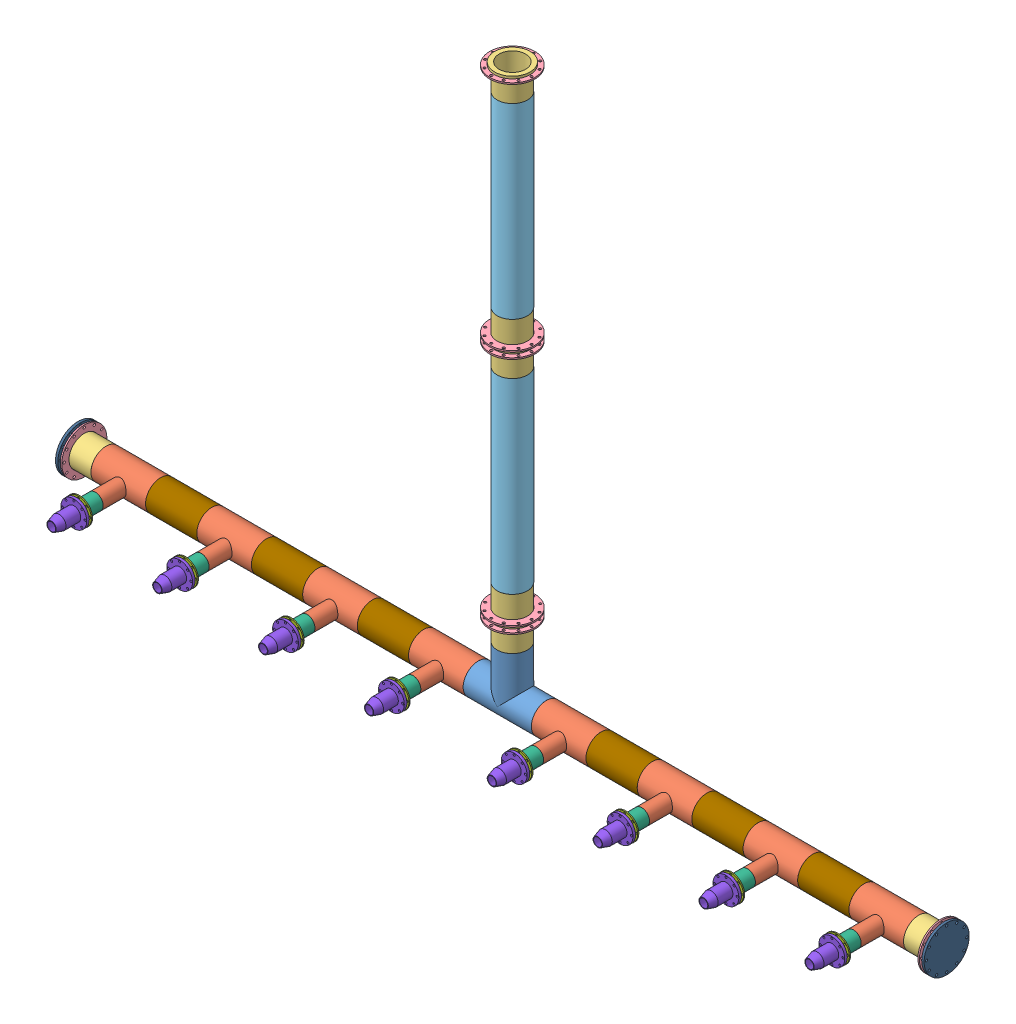
SolidWorks assembly Unflanged_Manifold_Assembly, configuration Default. Lengths in mm.
Overall size (9295.13 6167.88 1145.53).
57 component instances, 10 part files, 27 mates.
Components (placement in the parent):
- 12_NOM_Tee_Branch-1: 12_NOM_Tee_Branch [Default] x (0 1 0) z (-1 0 0) size (688.98 323.85 730.25)
- 12_to_6_Tee_Reducer-1: 12_to_6_Tee_Reducer [Default] at (657.225 0 0) x (1 0 0) z (0 -1 0) size (584.2 568.32 323.85)
- 12_NOM_Flange_Adapter-18: 12_NOM_Flange_Adapter [Default] at (0 801.37 0) x (0 -1 0) z (-0.329738 0 0.944073) size (274.32 381 381)
- Class_150_Slip-On_Plate_Flange-18: Class_150_Slip-On_Plate_Flange [Default] at (0 760.095 0) x (0.998909 0 0.04671) z (0 1 0) size (482.6 482.6 15.88)
- 12_NOM_Flange_Adapter-19: 12_NOM_Flange_Adapter [Default] at (0 801.37 0) x (0 1 0) z (0.329738 0 -0.944073) size (274.32 381 381)
- Class_150_Slip-On_Plate_Flange-19: Class_150_Slip-On_Plate_Flange [Default] at (0 842.645 0) x (0.998909 0 0.04671) z (0 -1 0) size (482.6 482.6 15.88)
- 12_NOM_Pipe_Segment-1: 12_NOM_Pipe_Segment [Default] at (0 3075.69 0) x (0 -1 0) z (0.028781 0 0.999586) size (2000 323.85 323.85)
- 12_NOM_Flange_Adapter-20: 12_NOM_Flange_Adapter [Default] at (0 3350.01 0) x (0 -1 0) z (-0.329738 0 0.944073) size (274.32 381 381)
- Class_150_Slip-On_Plate_Flange-20: Class_150_Slip-On_Plate_Flange [Default] at (0 3308.735 0) x (-0.998909 0 -0.04671) z (0 1 0) size (482.6 482.6 15.88)
- 12_NOM_Flange_Adapter-21: 12_NOM_Flange_Adapter [Default] at (0 5898.65 0) x (0 -1 0) z (-0.329738 0 0.944073) size (274.32 381 381)
- Class_150_Slip-On_Plate_Flange-21: Class_150_Slip-On_Plate_Flange [Default] at (0 5857.375 0) x (-0.998909 0 -0.04671) z (0 1 0) size (482.6 482.6 15.88)
- 12_NOM_Flange_Adapter-22: 12_NOM_Flange_Adapter [Default] at (0 3350.01 0) x (0 1 0) z (0.329738 0 -0.944073) size (274.32 381 381)
- Class_150_Slip-On_Plate_Flange-22: Class_150_Slip-On_Plate_Flange [Default] at (0 3375.41 0) x (0.998909 0 0.04671) z (0 1 0) size (482.6 482.6 15.88)
- 12_NOM_Pipe_Segment-2: 12_NOM_Pipe_Segment [Default] at (0 3624.33 0) x (0 1 0) z (-0.028781 0 -0.999586) size (2000 323.85 323.85)
- 6_NOM_Flange_Adapter-2: 6_NOM_Flange_Adapter [Default] at (657.225 0 609.6) x (0 0 -1) z (0.910925 0.412572 0) size (203.2 215.9 215.9)
- 6_NOM_Class_150_Slip-On_Plate_Flange-1: 6_NOM_Class_150_Slip-On_Plate_Flange [Default] at (657.225 0 576.58) size (279.4 279.4 12.7)
- Nozzle(Flanged)-1: Nozzle(Flanged) [Default] at (657.225 0 876.3) x (0 0 -1) z (0.92388 0.382683 0) size (266.7 275.84 275.84)
- 12_NOM_Horizontal_Pipe_Segment-1: 12_NOM_Horizontal_Pipe_Segment [Default] at (949.325 0 0) x (1 0 0) z (0 0.450094 0.892981) size (548.64 323.85 323.85)
- 12_to_6_Tee_Reducer-19: 12_to_6_Tee_Reducer [Default] at (1790.065 0 0) x (-1 0 0) z (0 1 0) size (584.2 568.32 323.85)
- 6_NOM_Flange_Adapter-10: 6_NOM_Flange_Adapter [Default] at (1790.065 0 609.6) x (0 0 -1) z (0.910925 -0.412572 0) size (203.2 215.9 215.9)
- 6_NOM_Class_150_Slip-On_Plate_Flange-9: 6_NOM_Class_150_Slip-On_Plate_Flange [Default] at (1790.065 0 576.58) size (279.4 279.4 12.7)
- Nozzle(Flanged)-9: Nozzle(Flanged) [Default] at (1790.065 0 876.3) x (0 0 -1) z (-0.92388 0.382683 0) size (266.7 275.84 275.84)
- 12_NOM_Horizontal_Pipe_Segment-2: 12_NOM_Horizontal_Pipe_Segment [Default] at (2630.805 0 0) x (-1 0 0) z (0 -0.450094 -0.892981) size (548.64 323.85 323.85)
- 12_to_6_Tee_Reducer-20: 12_to_6_Tee_Reducer [Default] at (2922.905 0 0) x (-1 0 0) z (0 1 0) size (584.2 568.32 323.85)
- 6_NOM_Flange_Adapter-11: 6_NOM_Flange_Adapter [Default] at (2922.905 0 609.6) x (0 0 -1) z (0.910925 -0.412572 0) size (203.2 215.9 215.9)
- Nozzle(Flanged)-10: Nozzle(Flanged) [Default] at (2922.905 0 876.3) x (0 0 -1) z (-0.92388 0.382683 0) size (266.7 275.84 275.84)
- 6_NOM_Class_150_Slip-On_Plate_Flange-10: 6_NOM_Class_150_Slip-On_Plate_Flange [Default] at (2922.905 0 576.58) size (279.4 279.4 12.7)
- 12_NOM_Horizontal_Pipe_Segment-3: 12_NOM_Horizontal_Pipe_Segment [Default] at (3215.005 0 0) x (1 0 0) z (0 0.450094 0.892981) size (548.64 323.85 323.85)
- 12_to_6_Tee_Reducer-21: 12_to_6_Tee_Reducer [Default] at (4055.745 0 0) x (1 0 0) z (0 -1 0) size (584.2 568.32 323.85)
- 6_NOM_Flange_Adapter-12: 6_NOM_Flange_Adapter [Default] at (4055.745 0 609.6) x (0 0 -1) z (0.910925 0.412572 0) size (203.2 215.9 215.9)
- 6_NOM_Class_150_Slip-On_Plate_Flange-11: 6_NOM_Class_150_Slip-On_Plate_Flange [Default] at (4055.745 0 576.58) size (279.4 279.4 12.7)
- Nozzle(Flanged)-11: Nozzle(Flanged) [Default] at (4055.745 0 876.3) x (0 0 -1) z (-0.92388 -0.382683 0) size (266.7 275.84 275.84)
- 12_NOM_Flange_Adapter-23: 12_NOM_Flange_Adapter [Default] at (4622.165 0 0) x (-1 0 0) z (0 -0.680898 -0.732378) size (274.32 381 381)
- Class_150_Slip-On_Plate_Flange-23: Class_150_Slip-On_Plate_Flange [Default] at (4580.89 0 0) x (0 0 -1) z (1 0 0) size (482.6 482.6 15.88)
- 12_NOM_Blind_Flange-3: 12_NOM_Blind_Flange [Default] at (4647.565 0 0) x (0 0 1) z (-1 0 0) size (482.6 482.6 25.4)
- 12_NOM_Flange_Adapter-24: 12_NOM_Flange_Adapter [Default] at (-4622.165 0 0) x (1 0 0) z (0 0.680898 0.732378) size (274.32 381 381)
- 12_NOM_Horizontal_Pipe_Segment-4: 12_NOM_Horizontal_Pipe_Segment [Default] at (-949.325 0 0) x (-1 0 0) z (0 -0.450094 -0.892981) size (548.64 323.85 323.85)
- 12_NOM_Horizontal_Pipe_Segment-5: 12_NOM_Horizontal_Pipe_Segment [Default] at (-3215.005 0 0) x (-1 0 0) z (0 -0.450094 -0.892981) size (548.64 323.85 323.85)
- Nozzle(Flanged)-12: Nozzle(Flanged) [Default] at (-4055.745 0 876.3) x (0 0 -1) z (-0.92388 0.382683 0) size (266.7 275.84 275.84)
- 12_to_6_Tee_Reducer-22: 12_to_6_Tee_Reducer [Default] at (-2922.905 0 0) x (1 0 0) z (0 -1 0) size (584.2 568.32 323.85)
- 6_NOM_Class_150_Slip-On_Plate_Flange-12: 6_NOM_Class_150_Slip-On_Plate_Flange [Default] at (-4055.745 0 576.58) x (-1 0 0) z (0 0 1) size (279.4 279.4 12.7)
- 6_NOM_Class_150_Slip-On_Plate_Flange-13: 6_NOM_Class_150_Slip-On_Plate_Flange [Default] at (-2922.905 0 576.58) x (-1 0 0) z (0 0 1) size (279.4 279.4 12.7)
- Nozzle(Flanged)-13: Nozzle(Flanged) [Default] at (-2922.905 0 876.3) x (0 0 -1) z (-0.92388 -0.382683 0) size (266.7 275.84 275.84)
- 6_NOM_Flange_Adapter-13: 6_NOM_Flange_Adapter [Default] at (-2922.905 0 609.6) x (0 0 -1) z (0.910925 0.412572 0) size (203.2 215.9 215.9)
- 12_NOM_Horizontal_Pipe_Segment-6: 12_NOM_Horizontal_Pipe_Segment [Default] at (-2630.805 0 0) x (1 0 0) z (0 0.450094 0.892981) size (548.64 323.85 323.85)
- 6_NOM_Flange_Adapter-14: 6_NOM_Flange_Adapter [Default] at (-4055.745 0 609.6) x (0 0 -1) z (0.910925 -0.412572 0) size (203.2 215.9 215.9)
- 12_to_6_Tee_Reducer-23: 12_to_6_Tee_Reducer [Default] at (-4055.745 0 0) x (-1 0 0) z (0 1 0) size (584.2 568.32 323.85)
- 12_to_6_Tee_Reducer-24: 12_to_6_Tee_Reducer [Default] at (-1790.065 0 0) x (1 0 0) z (0 -1 0) size (584.2 568.32 323.85)
- Class_150_Slip-On_Plate_Flange-24: Class_150_Slip-On_Plate_Flange [Default] at (-4580.89 0 0) x (0 0 -1) z (-1 0 0) size (482.6 482.6 15.88)
- 12_NOM_Blind_Flange-4: 12_NOM_Blind_Flange [Default] at (-4622.165 0 0) x (0 0 1) z (-1 0 0) size (482.6 482.6 25.4)
- 12_to_6_Tee_Reducer-25: 12_to_6_Tee_Reducer [Default] at (-657.225 0 0) x (-1 0 0) z (0 1 0) size (584.2 568.32 323.85)
- Nozzle(Flanged)-14: Nozzle(Flanged) [Default] at (-657.225 0 876.3) x (0 0 -1) z (0.92388 -0.382683 0) size (266.7 275.84 275.84)
- 6_NOM_Class_150_Slip-On_Plate_Flange-14: 6_NOM_Class_150_Slip-On_Plate_Flange [Default] at (-657.225 0 576.58) x (-1 0 0) z (0 0 1) size (279.4 279.4 12.7)
- 6_NOM_Flange_Adapter-15: 6_NOM_Flange_Adapter [Default] at (-657.225 0 609.6) x (0 0 -1) z (0.910925 -0.412572 0) size (203.2 215.9 215.9)
- 6_NOM_Flange_Adapter-16: 6_NOM_Flange_Adapter [Default] at (-1790.065 0 609.6) x (0 0 -1) z (0.910925 0.412572 0) size (203.2 215.9 215.9)
- 6_NOM_Class_150_Slip-On_Plate_Flange-15: 6_NOM_Class_150_Slip-On_Plate_Flange [Default] at (-1790.065 0 576.58) x (-1 0 0) z (0 0 1) size (279.4 279.4 12.7)
- Nozzle(Flanged)-15: Nozzle(Flanged) [Default] at (-1790.065 0 876.3) x (0 0 -1) z (-0.92388 -0.382683 0) size (266.7 275.84 275.84)
Mates (geometry in assembly coordinates):
- Concentric1: concentric aligned: cylinder of 12_NOM_Tee_Branch-1 through (-365.125 0 0) axis (1 0 0) radius 141.732
- Concentric2: concentric aligned: cylinder of 12_NOM_Tee_Branch-1 through (0 -400.8786 0) axis (0 1 0) radius 141.732
- Concentric3: concentric anti-aligned: cylinder of 12_NOM_Tee_Branch-1 through (-365.125 0 0) axis (1 0 0) radius 141.732; cylinder of 12_to_6_Tee_Reducer-1 through (657.225 0 0) axis (-1 0 0) radius 141.732
- Parallel1: parallel aligned: plane of 12_to_6_Tee_Reducer-1 through (657.225 0 406.4) normal (0 0 1)
- Coincident3: coincident anti-aligned: plane of 12_NOM_Tee_Branch-1 through (365.125 0 0) normal (1 0 0); plane of 12_to_6_Tee_Reducer-1 through (365.125 0 161.925) normal (-1 0 0)
- Concentric11: concentric aligned: cylinder of 12_NOM_Tee_Branch-1 through (0 -400.8786 0) axis (0 1 0) radius 141.732; cylinder of 12_NOM_Flange_Adapter-18 through (0 801.37 0) axis (0 1 0) radius 141.732
- Coincident11: coincident anti-aligned: plane of 12_NOM_Tee_Branch-1 through (0 527.05 0) normal (0 1 0); plane of 12_NOM_Flange_Adapter-18 through (133.8053 527.05 46.7344) normal (0 -1 0)
- Concentric12: concentric anti-aligned: cylinder of 12_NOM_Flange_Adapter-18 through (0 801.37 0) axis (0 1 0) radius 161.925; cylinder of Class_150_Slip-On_Plate_Flange-18 through (0 775.97 0) axis (0 -1 0) radius 163.576
- Coincident13: coincident anti-aligned: plane of 12_NOM_Flange_Adapter-18 through (152.869 775.97 53.3928) normal (0 -1 0); plane of Class_150_Slip-On_Plate_Flange-18 through (0 775.97 0) normal (0 1 0)
- Concentric13: concentric anti-aligned: cylinder of 12_NOM_Flange_Adapter-19 through (0 801.37 0) axis (0 -1 0) radius 141.732; cylinder of 12_NOM_Pipe_Segment-1 through (0 3075.69 0) axis (0 1 0) radius 141.732
- Coincident14: coincident anti-aligned: plane of 12_NOM_Flange_Adapter-19 through (133.8053 1075.69 46.7344) normal (0 1 0); plane of 12_NOM_Pipe_Segment-1 through (141.6733 1075.69 -4.0792) normal (0 -1 0)
- Concentric16: concentric aligned: cylinder of 12_to_6_Tee_Reducer-1 through (657.225 0 -208.306) axis (0 0 1) radius 73.6473; cylinder of 6_NOM_Flange_Adapter-2 through (657.225 0 609.6) axis (0 0 1) radius 73.6473
- Coincident16: coincident anti-aligned: plane of 12_to_6_Tee_Reducer-1 through (657.225 0 406.4) normal (0 0 1); plane of 6_NOM_Flange_Adapter-2 through (626.8402 67.0872 406.4) normal (0 0 -1)
- Concentric17: concentric anti-aligned: cylinder of 6_NOM_Flange_Adapter-2 through (657.225 0 609.6) axis (0 0 1) radius 84.1375; cylinder of 6_NOM_Class_150_Slip-On_Plate_Flange-1 through (657.225 0 589.28) axis (0 0 -1) radius 84.1375
- Coincident17: coincident anti-aligned: plane of 6_NOM_Flange_Adapter-2 through (622.5122 76.643 589.28) normal (0 0 -1); plane of 6_NOM_Class_150_Slip-On_Plate_Flange-1 through (657.225 0 589.28) normal (0 0 1)
- Concentric18: concentric aligned: cylinder of 6_NOM_Flange_Adapter-2 through (657.225 0 609.6) axis (0 0 1) radius 73.6473; cylinder of Nozzle(Flanged)-1 through (657.225 0 876.3) axis (0 0 1) radius 68.795
- Coincident18: coincident anti-aligned: plane of 6_NOM_Flange_Adapter-2 through (612.6879 98.3344 609.6) normal (0 0 1); plane of Nozzle(Flanged)-1 through (657.225 0 609.6) normal (0 0 -1)
- Concentric19: concentric aligned: cylinder of 6_NOM_Class_150_Slip-On_Plate_Flange-1 through (657.225 120.65 589.28) axis (0 0 -1) radius 11.176; cylinder of Nozzle(Flanged)-1 through (657.225 120.65 609.6) axis (0 0 -1) radius 11.176
- Concentric21: concentric aligned: cylinder of 12_to_6_Tee_Reducer-1 through (657.225 0 0) axis (-1 0 0) radius 141.732; cylinder of 12_NOM_Horizontal_Pipe_Segment-1 through (949.325 0 0) axis (-1 0 0) radius 141.732
- Coincident22: coincident anti-aligned: plane of 12_to_6_Tee_Reducer-1 through (949.325 0 161.925) normal (1 0 0); plane of 12_NOM_Horizontal_Pipe_Segment-1 through (949.325 126.564 -63.7927) normal (-1 0 0)
- Concentric22: concentric anti-aligned: cylinder of 12_to_6_Tee_Reducer-21 through (4055.745 0 0) axis (-1 0 0) radius 141.732; cylinder of 12_NOM_Flange_Adapter-23 through (4622.165 0 0) axis (1 0 0) radius 141.732
- Coincident23: coincident anti-aligned: plane of 12_to_6_Tee_Reducer-21 through (4347.845 0 161.925) normal (1 0 0); plane of 12_NOM_Flange_Adapter-23 through (4347.845 103.8015 -96.505) normal (-1 0 0)
- Concentric23: concentric anti-aligned: cylinder of 12_NOM_Flange_Adapter-23 through (4622.165 0 0) axis (1 0 0) radius 161.925; cylinder of Class_150_Slip-On_Plate_Flange-23 through (4596.765 0 0) axis (-1 0 0) radius 163.576
- Coincident24: coincident anti-aligned: plane of 12_NOM_Flange_Adapter-23 through (4596.765 118.5904 -110.2544) normal (-1 0 0); plane of Class_150_Slip-On_Plate_Flange-23 through (4596.765 0 0) normal (1 0 0)
- Coincident25: coincident anti-aligned: plane of 12_NOM_Flange_Adapter-23 through (4622.165 139.5181 -129.711) normal (1 0 0); plane of 12_NOM_Blind_Flange-3 through (4622.165 0 0) normal (-1 0 0)
- Concentric24: concentric anti-aligned: cylinder of Class_150_Slip-On_Plate_Flange-23 through (4596.765 0 0) axis (-1 0 0) radius 241.3; cylinder of 12_NOM_Blind_Flange-3 through (4622.165 0 0) axis (1 0 0) radius 241.3
- Concentric25: concentric anti-aligned: cylinder of Class_150_Slip-On_Plate_Flange-23 through (4596.765 -215.9 0) axis (-1 0 0) radius 12.7; cylinder of 12_NOM_Blind_Flange-3 through (4622.165 -215.9 0) axis (1 0 0) radius 12.7
